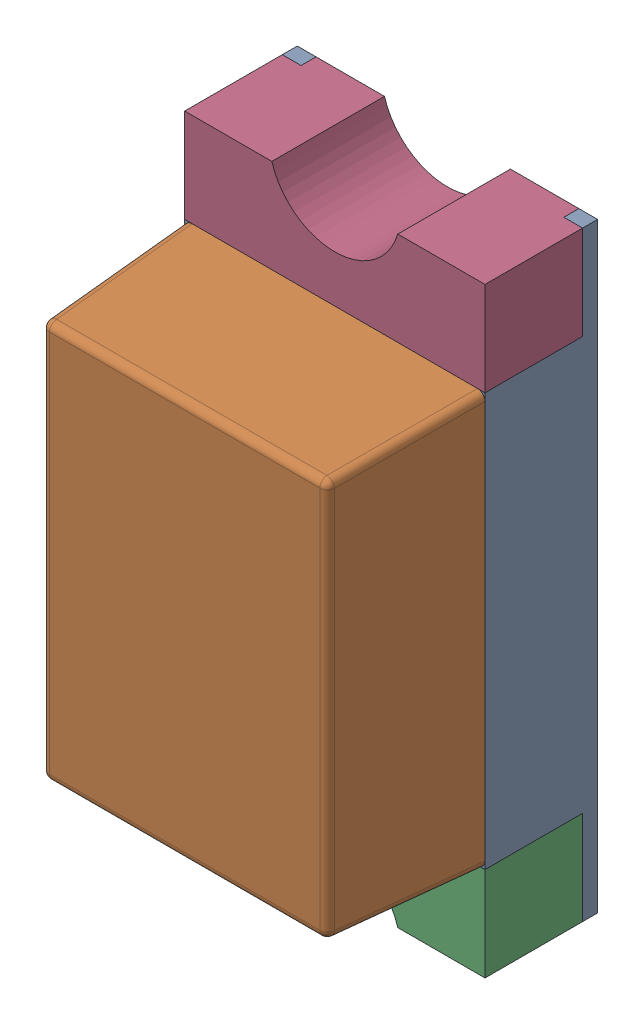
SolidWorks assembly LED201PCB, configuration Default. Lengths in mm.
Overall size (0.8 1.6 0.7).
6 component instances, 4 part files, 0 mates.
Components (placement in the parent):
- WL-SMCW_0603_LED-1: WL-SMCW_0603_LED [Default] at (91.8999 128.4001 0) x (0 1 0) z (0 0 1) size (1.6 0.8 0.7)
  - housing-1: housing [Default] at origin size (1.6 0.8 0.3)
  - cover-1: cover [Default] at (0 0 0.3) size (1.1 0.8 0.4)
  - base-1: base [Default] at (-0.675 0 0) size (0.45 0.8 0.3)
  - base-2: base [Default] at (0.675 0 0) x (-1 0 0) z (0 0 1) size (0.45 0.8 0.3)
  - Polarity_Mark-1: Polarity_Mark [Default] at (-0.675 0.35 0.3) size (0.25 0.1 0)
